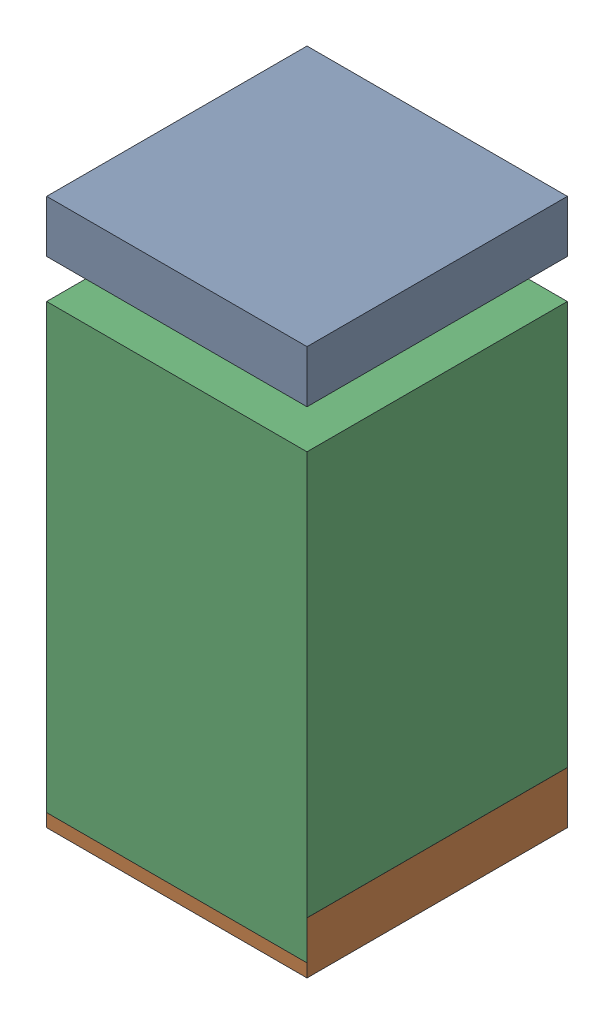
SolidWorks assembly C24, configuration Default. Lengths in mm.
Overall size (0.5 1.05 0.5).
6 component instances, 2 part files, 0 mates.
Components (placement in the parent):
- 810157360-1: 810157360 [Default] at (129.75 25.9 0) size (0.5 0.1 0.5)
  - Extruded_9-1: Extruded_9 [Default] at origin size (0.5 0.1 0.5)
- 810157360-2: 810157360 [Default] at (129.75 24.95 0) size (0.5 0.1 0.5)
  - Extruded_9-1: Extruded_9 [Default] at origin size (0.5 0.1 0.5)
- 810157104-1: 810157104 [Default] at (129.7499 25.3501 0) size (0.5 0.85 0.5)
  - Extruded_16-1: Extruded_16 [Default] at origin size (0.5 0.85 0.5)
